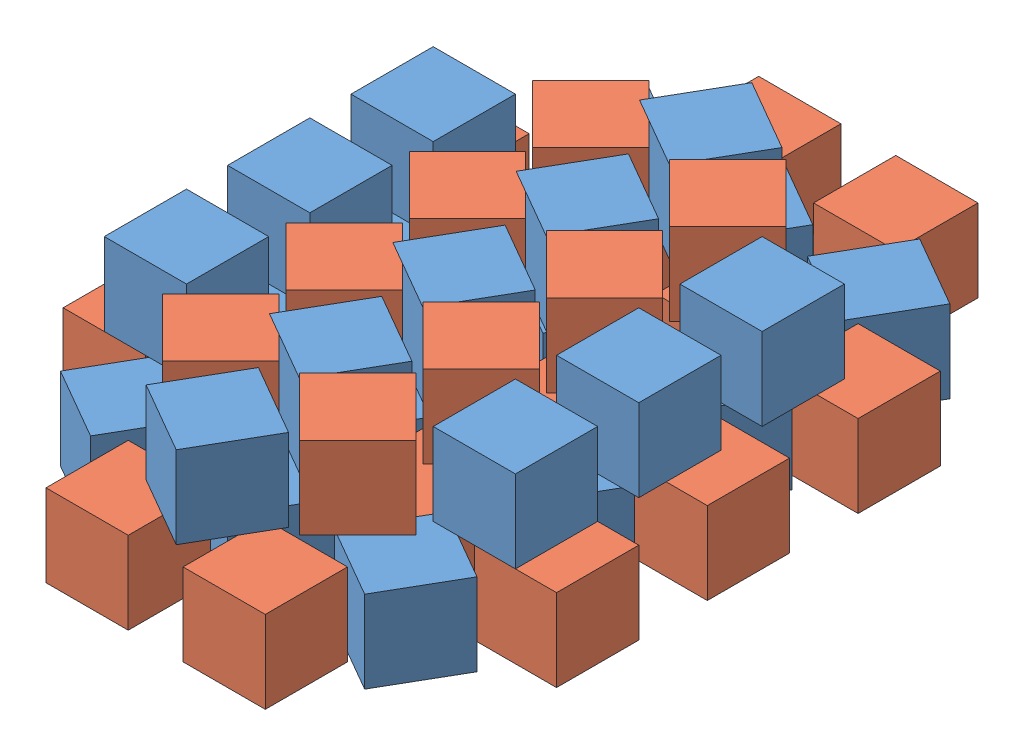
SolidWorks assembly FIELD_RelicRecovery_1718_RANDOM_GLYPHS_ASM, configuration Default. Lengths in mm.
Overall size (914.4 304.8 1320.8).
47 component instances, 2 part files, 0 mates.
Components (placement in the parent):
- FIELD_RelicRecovery_1718_GLYPH_BLACK-1: FIELD_RelicRecovery_1718_GLYPH_BLACK [Default] at (254 0 609.6) x (0.866025 0 0.5) z (-0.5 0 0.866025) size (152.4 152.4 152.4)
- FIELD_RelicRecovery_1718_GLYPH_BLACK-2: FIELD_RelicRecovery_1718_GLYPH_BLACK [Default] at (0 0 609.6) x (0.866025 0 0.5) z (-0.5 0 0.866025) size (152.4 152.4 152.4)
- FIELD_RelicRecovery_1718_GLYPH_BLACK-3: FIELD_RelicRecovery_1718_GLYPH_BLACK [Default] at (-254 0 609.6) x (0.866025 0 0.5) z (-0.5 0 0.866025) size (152.4 152.4 152.4)
- FIELD_RelicRecovery_1718_GLYPH_BLACK-4: FIELD_RelicRecovery_1718_GLYPH_BLACK [Default] at (254 0 317.5) x (0.866025 0 0.5) z (-0.5 0 0.866025) size (152.4 152.4 152.4)
- FIELD_RelicRecovery_1718_GLYPH_BLACK-5: FIELD_RelicRecovery_1718_GLYPH_BLACK [Default] at (0 0 317.5) x (0.866025 0 0.5) z (-0.5 0 0.866025) size (152.4 152.4 152.4)
- FIELD_RelicRecovery_1718_GLYPH_BLACK-6: FIELD_RelicRecovery_1718_GLYPH_BLACK [Default] at (-254 0 317.5) x (0.866025 0 0.5) z (-0.5 0 0.866025) size (152.4 152.4 152.4)
- FIELD_RelicRecovery_1718_GLYPH_BLACK-7: FIELD_RelicRecovery_1718_GLYPH_BLACK [Default] at (254 0 25.4) x (0.866025 0 0.5) z (-0.5 0 0.866025) size (152.4 152.4 152.4)
- FIELD_RelicRecovery_1718_GLYPH_BLACK-8: FIELD_RelicRecovery_1718_GLYPH_BLACK [Default] at (0 0 25.4) x (0.866025 0 0.5) z (-0.5 0 0.866025) size (152.4 152.4 152.4)
- FIELD_RelicRecovery_1718_GLYPH_BLACK-9: FIELD_RelicRecovery_1718_GLYPH_BLACK [Default] at (-254 0 25.4) x (0.866025 0 0.5) z (-0.5 0 0.866025) size (152.4 152.4 152.4)
- FIELD_RelicRecovery_1718_GLYPH_BLACK-10: FIELD_RelicRecovery_1718_GLYPH_BLACK [Default] at (254 0 -266.7) x (0.866025 0 0.5) z (-0.5 0 0.866025) size (152.4 152.4 152.4)
- FIELD_RelicRecovery_1718_GLYPH_BLACK-11: FIELD_RelicRecovery_1718_GLYPH_BLACK [Default] at (0 0 -266.7) x (0.866025 0 0.5) z (-0.5 0 0.866025) size (152.4 152.4 152.4)
- FIELD_RelicRecovery_1718_GLYPH_BLACK-12: FIELD_RelicRecovery_1718_GLYPH_BLACK [Default] at (-254 0 -266.7) x (0.866025 0 0.5) z (-0.5 0 0.866025) size (152.4 152.4 152.4)
- FIELD_RelicRecovery_1718_GLYPH_GREEN-1: FIELD_RelicRecovery_1718_GLYPH_GREEN [Default] at (146.05 0 762) size (152.4 152.4 152.4)
- FIELD_RelicRecovery_1718_GLYPH_GREEN-2: FIELD_RelicRecovery_1718_GLYPH_GREEN [Default] at (146.05 0 469.9) size (152.4 152.4 152.4)
- FIELD_RelicRecovery_1718_GLYPH_GREEN-3: FIELD_RelicRecovery_1718_GLYPH_GREEN [Default] at (146.05 0 177.8) size (152.4 152.4 152.4)
- FIELD_RelicRecovery_1718_GLYPH_GREEN-4: FIELD_RelicRecovery_1718_GLYPH_GREEN [Default] at (146.05 0 -114.3) size (152.4 152.4 152.4)
- FIELD_RelicRecovery_1718_GLYPH_GREEN-5: FIELD_RelicRecovery_1718_GLYPH_GREEN [Default] at (146.05 0 -406.4) size (152.4 152.4 152.4)
- FIELD_RelicRecovery_1718_GLYPH_GREEN-6: FIELD_RelicRecovery_1718_GLYPH_GREEN [Default] at (-107.95 0 762) size (152.4 152.4 152.4)
- FIELD_RelicRecovery_1718_GLYPH_GREEN-7: FIELD_RelicRecovery_1718_GLYPH_GREEN [Default] at (-107.95 0 469.9) size (152.4 152.4 152.4)
- FIELD_RelicRecovery_1718_GLYPH_GREEN-8: FIELD_RelicRecovery_1718_GLYPH_GREEN [Default] at (-107.95 0 177.8) size (152.4 152.4 152.4)
- FIELD_RelicRecovery_1718_GLYPH_GREEN-9: FIELD_RelicRecovery_1718_GLYPH_GREEN [Default] at (-107.95 0 -114.3) size (152.4 152.4 152.4)
- FIELD_RelicRecovery_1718_GLYPH_GREEN-10: FIELD_RelicRecovery_1718_GLYPH_GREEN [Default] at (-107.95 0 -406.4) size (152.4 152.4 152.4)
- FIELD_RelicRecovery_1718_GLYPH_GREEN-11: FIELD_RelicRecovery_1718_GLYPH_GREEN [Default] at (127 152.4 571.5) x (0.707107 0 0.707107) z (-0.707107 0 0.707107) size (152.4 152.4 152.4)
- FIELD_RelicRecovery_1718_GLYPH_GREEN-12: FIELD_RelicRecovery_1718_GLYPH_GREEN [Default] at (127 152.4 342.9) x (0.707107 0 0.707107) z (-0.707107 0 0.707107) size (152.4 152.4 152.4)
- FIELD_RelicRecovery_1718_GLYPH_GREEN-13: FIELD_RelicRecovery_1718_GLYPH_GREEN [Default] at (127 152.4 114.3) x (0.707107 0 0.707107) z (-0.707107 0 0.707107) size (152.4 152.4 152.4)
- FIELD_RelicRecovery_1718_GLYPH_GREEN-14: FIELD_RelicRecovery_1718_GLYPH_GREEN [Default] at (127 152.4 -114.3) x (0.707107 0 0.707107) z (-0.707107 0 0.707107) size (152.4 152.4 152.4)
- FIELD_RelicRecovery_1718_GLYPH_GREEN-15: FIELD_RelicRecovery_1718_GLYPH_GREEN [Default] at (-127 152.4 571.5) x (0.707107 0 0.707107) z (-0.707107 0 0.707107) size (152.4 152.4 152.4)
- FIELD_RelicRecovery_1718_GLYPH_GREEN-16: FIELD_RelicRecovery_1718_GLYPH_GREEN [Default] at (-127 152.4 342.9) x (0.707107 0 0.707107) z (-0.707107 0 0.707107) size (152.4 152.4 152.4)
- FIELD_RelicRecovery_1718_GLYPH_GREEN-17: FIELD_RelicRecovery_1718_GLYPH_GREEN [Default] at (-127 152.4 114.3) x (0.707107 0 0.707107) z (-0.707107 0 0.707107) size (152.4 152.4 152.4)
- FIELD_RelicRecovery_1718_GLYPH_GREEN-18: FIELD_RelicRecovery_1718_GLYPH_GREEN [Default] at (-127 152.4 -114.3) x (0.707107 0 0.707107) z (-0.707107 0 0.707107) size (152.4 152.4 152.4)
- FIELD_RelicRecovery_1718_GLYPH_BLACK-13: FIELD_RelicRecovery_1718_GLYPH_BLACK [Default] at (0 152.4 704.85) x (0.866025 0 0.5) z (-0.5 0 0.866025) size (152.4 152.4 152.4)
- FIELD_RelicRecovery_1718_GLYPH_BLACK-14: FIELD_RelicRecovery_1718_GLYPH_BLACK [Default] at (0 152.4 476.25) x (0.866025 0 0.5) z (-0.5 0 0.866025) size (152.4 152.4 152.4)
- FIELD_RelicRecovery_1718_GLYPH_BLACK-15: FIELD_RelicRecovery_1718_GLYPH_BLACK [Default] at (0 152.4 247.65) x (0.866025 0 0.5) z (-0.5 0 0.866025) size (152.4 152.4 152.4)
- FIELD_RelicRecovery_1718_GLYPH_BLACK-16: FIELD_RelicRecovery_1718_GLYPH_BLACK [Default] at (0 152.4 19.05) x (0.866025 0 0.5) z (-0.5 0 0.866025) size (152.4 152.4 152.4)
- FIELD_RelicRecovery_1718_GLYPH_BLACK-17: FIELD_RelicRecovery_1718_GLYPH_BLACK [Default] at (0 152.4 -209.55) x (0.866025 0 0.5) z (-0.5 0 0.866025) size (152.4 152.4 152.4)
- FIELD_RelicRecovery_1718_GLYPH_GREEN-19: FIELD_RelicRecovery_1718_GLYPH_GREEN [Default] at (381 0 457.2) size (152.4 152.4 152.4)
- FIELD_RelicRecovery_1718_GLYPH_GREEN-20: FIELD_RelicRecovery_1718_GLYPH_GREEN [Default] at (381 0 177.8) size (152.4 152.4 152.4)
- FIELD_RelicRecovery_1718_GLYPH_GREEN-21: FIELD_RelicRecovery_1718_GLYPH_GREEN [Default] at (381 0 -101.6) size (152.4 152.4 152.4)
- FIELD_RelicRecovery_1718_GLYPH_GREEN-22: FIELD_RelicRecovery_1718_GLYPH_GREEN [Default] at (-381 0 457.2) size (152.4 152.4 152.4)
- FIELD_RelicRecovery_1718_GLYPH_GREEN-23: FIELD_RelicRecovery_1718_GLYPH_GREEN [Default] at (-381 0 177.8) size (152.4 152.4 152.4)
- FIELD_RelicRecovery_1718_GLYPH_GREEN-24: FIELD_RelicRecovery_1718_GLYPH_GREEN [Default] at (-381 0 -101.6) size (152.4 152.4 152.4)
- FIELD_RelicRecovery_1718_GLYPH_BLACK-18: FIELD_RelicRecovery_1718_GLYPH_BLACK [Default] at (304.8 152.4 457.2) size (152.4 152.4 152.4)
- FIELD_RelicRecovery_1718_GLYPH_BLACK-19: FIELD_RelicRecovery_1718_GLYPH_BLACK [Default] at (-304.8 152.4 457.2) size (152.4 152.4 152.4)
- FIELD_RelicRecovery_1718_GLYPH_BLACK-20: FIELD_RelicRecovery_1718_GLYPH_BLACK [Default] at (304.8 152.4 228.6) size (152.4 152.4 152.4)
- FIELD_RelicRecovery_1718_GLYPH_BLACK-21: FIELD_RelicRecovery_1718_GLYPH_BLACK [Default] at (-304.8 152.4 228.6) size (152.4 152.4 152.4)
- FIELD_RelicRecovery_1718_GLYPH_BLACK-22: FIELD_RelicRecovery_1718_GLYPH_BLACK [Default] at (304.8 152.4 0) size (152.4 152.4 152.4)
- FIELD_RelicRecovery_1718_GLYPH_BLACK-23: FIELD_RelicRecovery_1718_GLYPH_BLACK [Default] at (-304.8 152.4 0) size (152.4 152.4 152.4)
